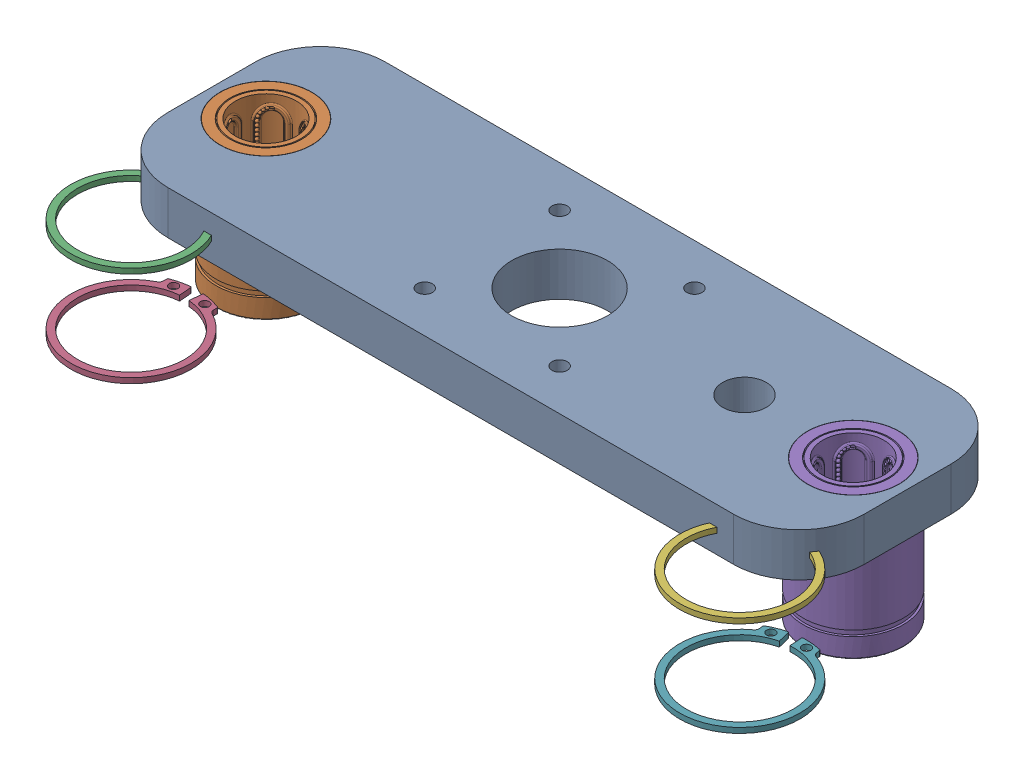
SolidWorks assembly V2_TSA machine motor on slider 13mmV2, configuration Default. Lengths in mm.
Overall size (169.14 32 71.38).
3 component instances, 2 part files, 4 mates.
Components (placement in the parent):
- V2_TSA machine 1m bottom motor plate 13mm bearingV2-2: V2_TSA machine 1m bottom motor plate 13mm bearingV2 [Default] at (-240.7221 1.8373 122.3806) size (160 10 50)
- V2_13mm LINEAR BALL BEARNGV2-1: V2_13mm LINEAR BALL BEARNGV2 [61205K78] at (-308.2221 -4.1627 122.3806) x (1 0 0) z (0 -1 0) size (27.66 56.33 32)
- V2_13mm LINEAR BALL BEARNGV2-2: V2_13mm LINEAR BALL BEARNGV2 [61205K78] at (-173.2221 -4.1627 122.3806) x (0.989025 0 -0.147748) z (0 -1 0) size (27.66 56.33 32)
Mates (geometry in assembly coordinates):
- Concentric1: concentric anti-aligned: cylinder of V2_TSA machine 1m bottom motor plate 13mm bearing-1 through (-308.2221 11.8373 122.3806) axis (0 -1 0) radius 10.55; cylinder of 13mm LINEAR BALL BEARNG-1 through (-308.2221 -20.1627 122.3806) axis (0 1 0) radius 11.5
- Concentric2: concentric anti-aligned: cylinder of V2_TSA machine 1m bottom motor plate 13mm bearing-1 through (-173.2221 11.8373 122.3806) axis (0 -1 0) radius 10.55; cylinder of 13mm LINEAR BALL BEARNG-2 through (-173.2221 -20.1627 122.3806) axis (0 1 0) radius 11.5
- Coincident5: coincident aligned: plane of V2_TSA machine 1m bottom motor plate 13mm bearing-1 through (-240.7221 11.8373 122.3806) normal (0 1 0); plane of 13mm LINEAR BALL BEARNG-2 through (-173.2221 11.8373 122.3806) normal (0 1 0)
- Coincident2: coincident aligned: plane of V2_TSA machine 1m bottom motor plate 13mm bearing-1 through (-240.7221 11.8373 122.3806) normal (0 1 0); plane of 13mm LINEAR BALL BEARNG-1 through (-308.2221 11.8373 122.3806) normal (0 1 0)
